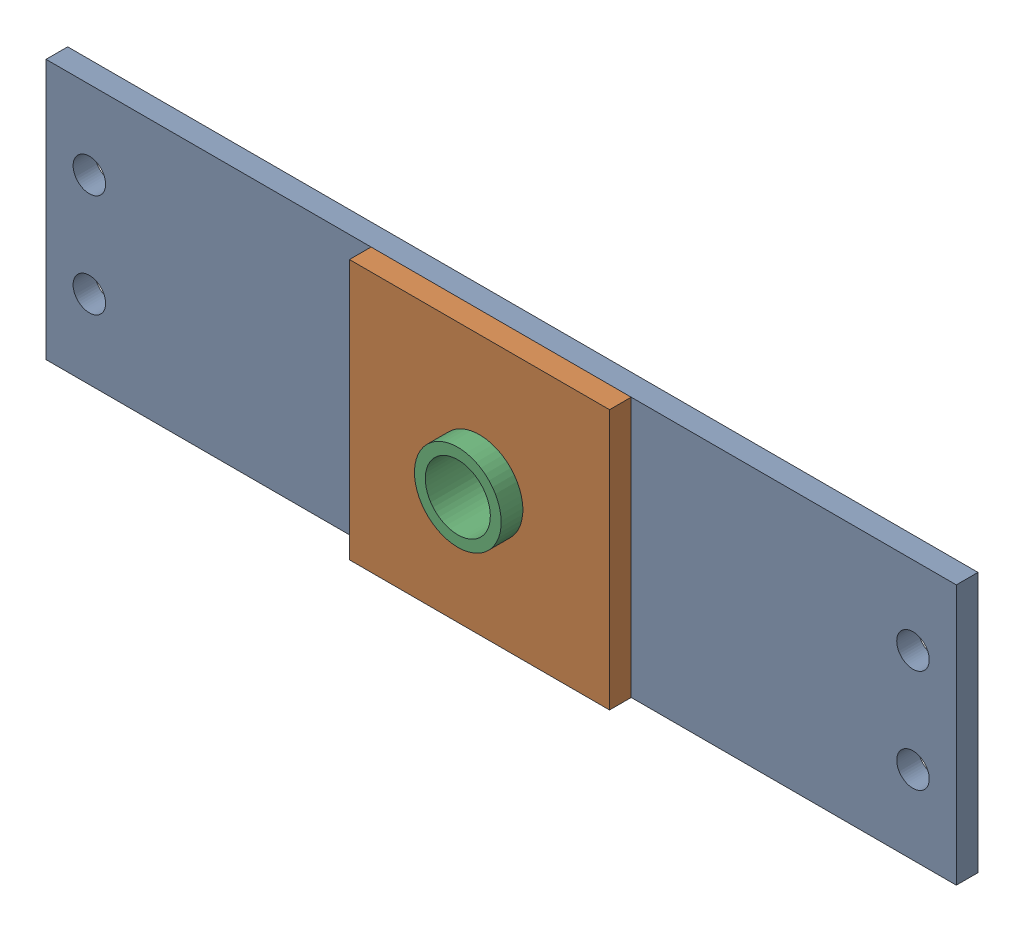
SolidWorks assembly Base Plate Ass-1, configuration Default. Lengths in mm.
Overall size (533.4 152.4 38.1).
3 component instances, 3 part files, 0 mates.
Components (placement in the parent):
- Base plate update-1: Base plate update [Default] at (-316.9216 -80.8539 23.313) size (533.4 152.4 12.7)
- Base Plate Support-1: Base Plate Support [Default] at (-126.4216 -80.8539 36.013) size (152.4 152.4 12.7)
- 01-109-00-0-1: 01-109-00-0 [Default] at (-50.2216 -4.6539 23.313) x (1 0 0) z (0 -1 0) size (50.8 38.1 50.8)
